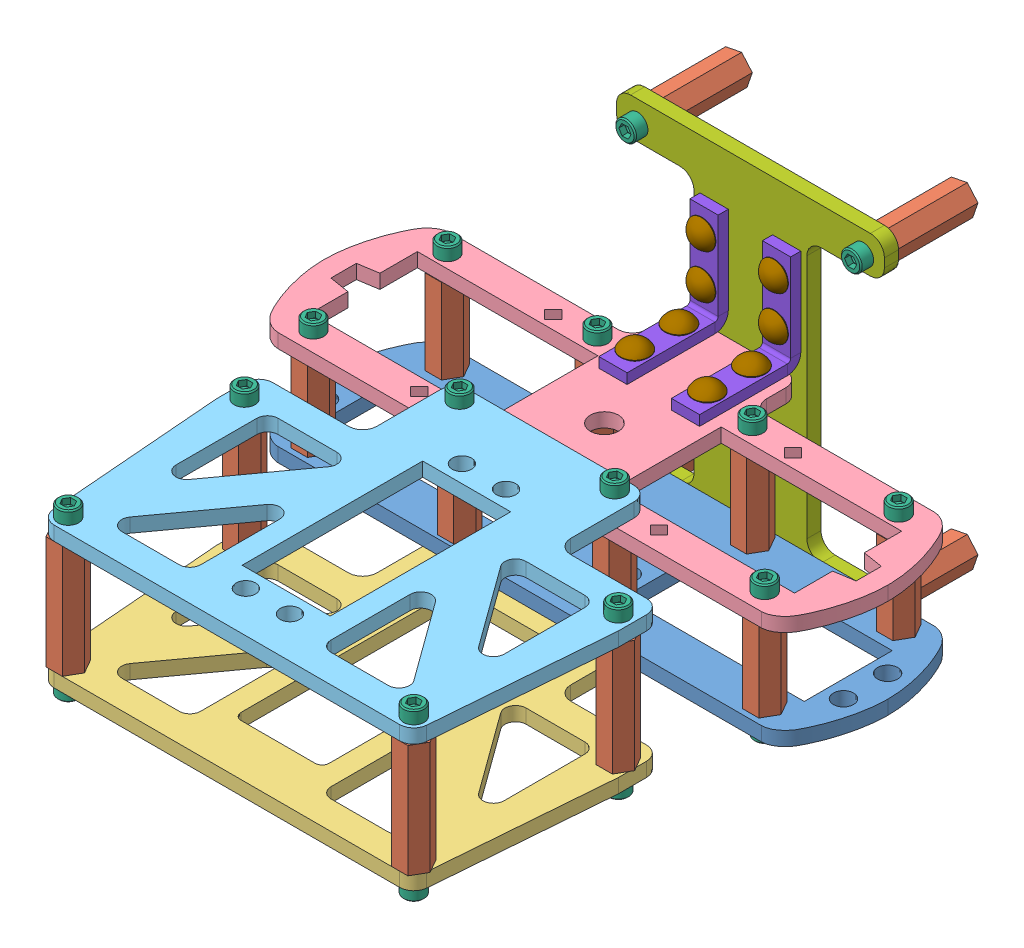
SolidWorks assembly BT-03, configuration Default. Lengths in mm.
Overall size (126.92 78.31 140.07).
59 component instances, 9 part files, 133 mates.
Components (placement in the parent):
- BT-03-001-1: BT-03-001 [Default] x (1 0 0) z (0 1 0) size (126.92 38.86 3.17)
- STANDOFF-250-HEX-FF-9: STANDOFF-250-HEX-FF [NHS-03] at (12.4427 -3.175 39.3112) x (0 -1 0) z (1 0 0) size (25.4 6.35 7.33)
- STANDOFF-250-HEX-FF-10: STANDOFF-250-HEX-FF [NHS-03] at (15.6177 -3.175 82.1737) x (0 -1 0) z (1 0 0) size (25.4 6.35 7.33)
- STANDOFF-250-HEX-FF-11: STANDOFF-250-HEX-FF [NHS-03] at (96.5802 -3.175 39.3112) x (0 -1 0) z (1 0 0) size (25.4 6.35 7.33)
- STANDOFF-250-HEX-FF-12: STANDOFF-250-HEX-FF [NHS-03] at (93.4052 -3.175 82.1737) x (0 -1 0) z (1 0 0) size (25.4 6.35 7.33)
- STANDOFF-250-HEX-FF-1: STANDOFF-250-HEX-FF [NHS-02] at (3.7114 0 -15.0855) x (0 -1 0) z (1 0 0) size (19.05 6.35 7.33)
- STANDOFF-250-HEX-FF-2: STANDOFF-250-HEX-FF [NHS-02] at (37.0489 0 -15.4987) x (0 -1 0) z (1 0 0) size (19.05 6.35 7.33)
- STANDOFF-250-HEX-FF-3: STANDOFF-250-HEX-FF [NHS-02] at (3.7114 0 15.0855) x (0 -1 0) z (1 0 0) size (19.05 6.35 7.33)
- STANDOFF-250-HEX-FF-4: STANDOFF-250-HEX-FF [NHS-02] at (37.0489 0 15.4987) x (0 -1 0) z (1 0 0) size (19.05 6.35 7.33)
- STANDOFF-250-HEX-FF-5: STANDOFF-250-HEX-FF [NHS-02] at (71.9739 0 -15.4987) x (0 -1 0) z (1 0 0) size (19.05 6.35 7.33)
- STANDOFF-250-HEX-FF-6: STANDOFF-250-HEX-FF [NHS-02] at (105.3114 0 -15.0855) x (0 -1 0) z (1 0 0) size (19.05 6.35 7.33)
- STANDOFF-250-HEX-FF-7: STANDOFF-250-HEX-FF [NHS-02] at (71.9739 0 15.4987) x (0 -1 0) z (1 0 0) size (19.05 6.35 7.33)
- STANDOFF-250-HEX-FF-8: STANDOFF-250-HEX-FF [NHS-02] at (105.3114 0 15.0855) x (0 -1 0) z (1 0 0) size (19.05 6.35 7.33)
- BT-03-004-1: BT-03-004 [Default] at (54.5114 -3.175 12.3237) x (1 0 0) z (0 -1 0) size (90.49 73.03 3.17)
- BT-03-002-1: BT-03-002 [Default] at (0 19.05 0) x (1 0 0) z (0 -1 0) size (126.92 49.62 3.17)
- BT-03-003-1: BT-03-003 [Default] at (54.5114 25.4 12.3237) x (1 0 0) z (0 -1 0) size (90.49 73.03 3.17)
- 4-40 x 0.250 SHCS (SHS-01)-1: 4-40 x 0.250 SHCS (SHS-01) [Default] at (3.7114 -6.0198 -15.0855) x (0 1 0) z (0 0 1) size (9.19 4.65 4.65)
- 4-40 x 0.250 SHCS (SHS-01)-2: 4-40 x 0.250 SHCS (SHS-01) [Default] at (37.0489 -6.0198 -15.4987) x (0 1 0) z (0 0 1) size (9.19 4.65 4.65)
- 4-40 x 0.250 SHCS (SHS-01)-3: 4-40 x 0.250 SHCS (SHS-01) [Default] at (3.7114 -6.0198 15.0855) x (0 1 0) z (0 0 1) size (9.19 4.65 4.65)
- 4-40 x 0.250 SHCS (SHS-01)-4: 4-40 x 0.250 SHCS (SHS-01) [Default] at (12.4427 -9.1948 39.3112) x (0 1 0) z (0 0 1) size (9.19 4.65 4.65)
- 4-40 x 0.250 SHCS (SHS-01)-5: 4-40 x 0.250 SHCS (SHS-01) [Default] at (37.0489 -9.1948 15.4987) x (0 1 0) z (0 0 1) size (9.19 4.65 4.65)
- 4-40 x 0.250 SHCS (SHS-01)-6: 4-40 x 0.250 SHCS (SHS-01) [Default] at (71.9739 -6.0198 -15.4987) x (0 1 0) z (0 0 1) size (9.19 4.65 4.65)
- 4-40 x 0.250 SHCS (SHS-01)-7: 4-40 x 0.250 SHCS (SHS-01) [Default] at (15.6177 -9.1948 82.1737) x (0 1 0) z (0 0 1) size (9.19 4.65 4.65)
- 4-40 x 0.250 SHCS (SHS-01)-8: 4-40 x 0.250 SHCS (SHS-01) [Default] at (71.9739 -9.1948 15.4987) x (0 1 0) z (0 0 1) size (9.19 4.65 4.65)
- 4-40 x 0.250 SHCS (SHS-01)-9: 4-40 x 0.250 SHCS (SHS-01) [Default] at (105.3114 -6.0198 -15.0855) x (0 1 0) z (0 0 1) size (9.19 4.65 4.65)
- 4-40 x 0.250 SHCS (SHS-01)-10: 4-40 x 0.250 SHCS (SHS-01) [Default] at (105.3114 -6.0198 15.0855) x (0 1 0) z (0 0 1) size (9.19 4.65 4.65)
- 4-40 x 0.250 SHCS (SHS-01)-11: 4-40 x 0.250 SHCS (SHS-01) [Default] at (96.5802 -9.1948 39.3112) x (0 1 0) z (0 0 1) size (9.19 4.65 4.65)
- 4-40 x 0.250 SHCS (SHS-01)-12: 4-40 x 0.250 SHCS (SHS-01) [Default] at (93.4052 -9.1948 82.1737) x (0 1 0) z (0 0 1) size (9.19 4.65 4.65)
- 4-40 x 0.250 SHCS (SHS-01)-13: 4-40 x 0.250 SHCS (SHS-01) [Default] at (15.6177 28.2448 82.1737) x (0 -1 0) z (0 0 1) size (9.19 4.65 4.65)
- 4-40 x 0.250 SHCS (SHS-01)-14: 4-40 x 0.250 SHCS (SHS-01) [Default] at (12.4427 28.2448 39.3112) x (0 -1 0) z (0 0 1) size (9.19 4.65 4.65)
- 4-40 x 0.250 SHCS (SHS-01)-15: 4-40 x 0.250 SHCS (SHS-01) [Default] at (3.7114 25.0698 15.0855) x (0 -1 0) z (0 0 1) size (9.19 4.65 4.65)
- 4-40 x 0.250 SHCS (SHS-01)-16: 4-40 x 0.250 SHCS (SHS-01) [Default] at (3.7114 25.0698 -15.0855) x (0 -1 0) z (0 0 1) size (9.19 4.65 4.65)
- 4-40 x 0.250 SHCS (SHS-01)-17: 4-40 x 0.250 SHCS (SHS-01) [Default] at (37.0489 25.0698 -15.4987) x (0 -1 0) z (0 0 1) size (9.19 4.65 4.65)
- 4-40 x 0.250 SHCS (SHS-01)-18: 4-40 x 0.250 SHCS (SHS-01) [Default] at (37.0489 28.2448 15.4987) x (0 -1 0) z (0 0 1) size (9.19 4.65 4.65)
- 4-40 x 0.250 SHCS (SHS-01)-19: 4-40 x 0.250 SHCS (SHS-01) [Default] at (71.9739 25.0698 -15.4987) x (0 -1 0) z (0 0 1) size (9.19 4.65 4.65)
- 4-40 x 0.250 SHCS (SHS-01)-20: 4-40 x 0.250 SHCS (SHS-01) [Default] at (71.9739 28.2448 15.4987) x (0 -1 0) z (0 0 1) size (9.19 4.65 4.65)
- 4-40 x 0.250 SHCS (SHS-01)-21: 4-40 x 0.250 SHCS (SHS-01) [Default] at (96.5802 28.2448 39.3112) x (0 -1 0) z (0 0 1) size (9.19 4.65 4.65)
- 4-40 x 0.250 SHCS (SHS-01)-22: 4-40 x 0.250 SHCS (SHS-01) [Default] at (105.3114 25.0698 15.0855) x (0 -1 0) z (0 0 1) size (9.19 4.65 4.65)
- 4-40 x 0.250 SHCS (SHS-01)-23: 4-40 x 0.250 SHCS (SHS-01) [Default] at (105.3114 25.0698 -15.0855) x (0 -1 0) z (0 0 1) size (9.19 4.65 4.65)
- 4-40 x 0.250 SHCS (SHS-01)-24: 4-40 x 0.250 SHCS (SHS-01) [Default] at (93.4052 28.2448 82.1737) x (0 -1 0) z (0 0 1) size (9.19 4.65 4.65)
- BT-03-005-2: BT-03-005 [Default] at (54.5127 56.2839 -35.6692) x (0 -1 0) z (0 0 1) size (78.18 60.32 3.17)
- STANDOFF-250-HEX-FF-13: STANDOFF-250-HEX-FF [NHS-02] at (29.1127 51.4071 -35.6692) x (0 0 1) z (0.656253 -0.754541 0) size (19.05 6.35 7.33)
- 4-40 x 0.250 SHCS (SHS-01)-25: 4-40 x 0.250 SHCS (SHS-01) [Default] at (29.1127 51.4071 -29.6494) x (0 0 -1) z (0.847919 0.530126 0) size (9.19 4.65 4.65)
- STANDOFF-250-HEX-FF-14: STANDOFF-250-HEX-FF [NHS-02] at (79.9127 51.4071 -35.6692) x (0 0 1) z (0.656253 -0.754541 0) size (19.05 6.35 7.33)
- STANDOFF-250-HEX-FF-15: STANDOFF-250-HEX-FF [NHS-02] at (79.9127 -17.1729 -35.6692) x (0 0 1) z (0.656253 -0.754541 0) size (19.05 6.35 7.33)
- STANDOFF-250-HEX-FF-16: STANDOFF-250-HEX-FF [NHS-02] at (29.1127 -17.1729 -35.6692) x (0 0 1) z (0.656253 -0.754541 0) size (19.05 6.35 7.33)
- 4-40 x 0.250 SHCS (SHS-01)-26: 4-40 x 0.250 SHCS (SHS-01) [Default] at (79.9127 51.4071 -29.6494) x (0 0 -1) z (0.847919 0.530126 0) size (9.19 4.65 4.65)
- 4-40 x 0.250 SHCS (SHS-01)-27: 4-40 x 0.250 SHCS (SHS-01) [Default] at (79.9127 -17.1729 -29.6494) x (0 0 -1) z (0.847919 0.530126 0) size (9.19 4.65 4.65)
- 4-40 x 0.250 SHCS (SHS-01)-28: 4-40 x 0.250 SHCS (SHS-01) [Default] at (29.1127 -17.1729 -29.6494) x (0 0 -1) z (0.847919 0.530126 0) size (9.19 4.65 4.65)
- ASB-02-1: ASB-02 [Default] at (46.3516 22.225 -32.4942) x (0 0 1) z (-1 0 0) size (22.78 22.78 6.35)
- ASB-02-2: ASB-02 [Default] at (62.6711 22.225 -32.4942) x (0 0 1) z (-1 0 0) size (22.78 22.78 6.35)
- NSRF-01-1: NSRF-01 [Default] at (46.3516 27.1043 -14.6126) x (0 -1 0) z (0 0 1) size (9.65 6.35 6.35)
- NSRF-01-2: NSRF-01 [Default] at (46.3516 27.1043 -24.5516) x (0 -1 0) z (0 0 1) size (9.65 6.35 6.35)
- NSRF-01-3: NSRF-01 [Default] at (46.3516 40.1066 -27.6149) x (0 0 -1) z (0.995672 0.092934 0) size (9.65 6.35 6.35)
- NSRF-01-4: NSRF-01 [Default] at (62.6711 27.1043 -14.6126) x (0 -1 0) z (0 0 1) size (9.65 6.35 6.35)
- NSRF-01-5: NSRF-01 [Default] at (62.6711 27.1043 -24.5516) x (0 -1 0) z (0 0 1) size (9.65 6.35 6.35)
- NSRF-01-6: NSRF-01 [Default] at (62.6711 40.1066 -27.6149) x (0 0 -1) z (1 0 0) size (9.65 6.35 6.35)
- NSRF-01-7: NSRF-01 [Default] at (46.3516 30.1676 -27.6149) x (0 0 -1) z (1 0 0) size (9.65 6.35 6.35)
- NSRF-01-8: NSRF-01 [Default] at (62.6711 30.1676 -27.6149) x (0 0 -1) z (1 0 0) size (9.65 6.35 6.35)
Mates (geometry in assembly coordinates):
- Coincident1: coincident aligned: plane of BT-03-001-1 through (0 0 0) normal (1 0 0); plane of assembly
- Coincident2: coincident anti-aligned: plane of BT-03-001-1 through (0 0 0) normal (0 0 -1); plane of assembly
- Coincident3: coincident aligned: plane of BT-03-001-1 through (0 0 0) normal (0 1 0); plane of assembly
- Coincident4: coincident anti-aligned: plane of BT-03-001-1 through (-6.866 0 -11.2321) normal (0 1 0); plane of STANDOFF-250-HEX-FF-1
- Concentric1: concentric anti-aligned: circle of BT-03-001-1 centre (3.7114 0 -15.0855) axis (0 1 0); cylinder of STANDOFF-250-HEX-FF-1
- Parallel1: parallel aligned: plane of BT-03-001-1 through (0 -3.175 -9.906) normal (0 0 1); plane of STANDOFF-250-HEX-FF-1
- Concentric2: concentric anti-aligned: circle of BT-03-001-1 centre (37.0489 0 -15.4987) axis (0 1 0); cylinder of STANDOFF-250-HEX-FF-2
- Coincident6: coincident anti-aligned: plane of BT-03-001-1 through (-6.866 0 -11.2321) normal (0 1 0); plane of STANDOFF-250-HEX-FF-2
- Parallel2: parallel aligned: plane of BT-03-001-1 through (0 -3.175 -9.906) normal (0 0 1); plane of STANDOFF-250-HEX-FF-2
- Concentric3: concentric aligned: circle of BT-03-001-1 centre (3.7114 0 15.0855) axis (0 -1 0); cylinder of STANDOFF-250-HEX-FF-3
- Coincident7: coincident anti-aligned: plane of BT-03-001-1 through (-6.866 0 -11.2321) normal (0 1 0); plane of STANDOFF-250-HEX-FF-3
- Parallel3: parallel aligned: plane of BT-03-001-1 through (108.8801 -3.175 19.431) normal (0 0 1); plane of STANDOFF-250-HEX-FF-3
- Concentric4: concentric aligned: circle of BT-03-001-1 centre (37.0489 0 15.4987) axis (0 -1 0); cylinder of STANDOFF-250-HEX-FF-4
- Coincident9: coincident anti-aligned: plane of BT-03-001-1 through (-6.866 0 -11.2321) normal (0 1 0); plane of STANDOFF-250-HEX-FF-4
- Parallel4: parallel aligned: plane of BT-03-001-1 through (108.8801 -3.175 19.431) normal (0 0 1); plane of STANDOFF-250-HEX-FF-4
- Coincident10: coincident anti-aligned: plane of BT-03-001-1 through (-6.866 0 -11.2321) normal (0 1 0); plane of STANDOFF-250-HEX-FF-5
- Concentric5: concentric aligned: circle of BT-03-001-1 centre (71.9739 0 -15.4987) axis (0 -1 0); cylinder of STANDOFF-250-HEX-FF-5
- Parallel5: parallel aligned: plane of BT-03-001-1 through (68.3826 -3.175 -9.906) normal (0 0 1); plane of STANDOFF-250-HEX-FF-5
- Concentric6: concentric aligned: circle of BT-03-001-1 centre (105.3114 0 -15.0855) axis (0 -1 0); cylinder of STANDOFF-250-HEX-FF-6
- Coincident11: coincident anti-aligned: plane of BT-03-001-1 through (-6.866 0 -11.2321) normal (0 1 0); plane of STANDOFF-250-HEX-FF-6
- Parallel6: parallel aligned: plane of BT-03-001-1 through (68.3826 -3.175 -9.906) normal (0 0 1); plane of STANDOFF-250-HEX-FF-6
- Concentric7: concentric anti-aligned: circle of BT-03-001-1 centre (71.9739 0 15.4987) axis (0 1 0); cylinder of STANDOFF-250-HEX-FF-7
- Concentric8: concentric anti-aligned: circle of BT-03-001-1 centre (105.3114 0 15.0855) axis (0 1 0); cylinder of STANDOFF-250-HEX-FF-8
- Coincident12: coincident anti-aligned: plane of BT-03-001-1 through (-6.866 0 -11.2321) normal (0 1 0); plane of STANDOFF-250-HEX-FF-8
- Parallel7: parallel aligned: plane of BT-03-001-1 through (108.8801 -3.175 19.431) normal (0 0 1); plane of STANDOFF-250-HEX-FF-8
- Coincident13: coincident anti-aligned: plane of BT-03-001-1 through (-6.866 0 -11.2321) normal (0 1 0); plane of STANDOFF-250-HEX-FF-7
- Parallel8: parallel aligned: plane of BT-03-001-1 through (108.8801 -3.175 19.431) normal (0 0 1); plane of STANDOFF-250-HEX-FF-7
- Coincident14: coincident anti-aligned: plane of BT-03-001-1 through (-6.866 -3.175 -11.2321) normal (0 -1 0); plane of BT-03-004-1 through (96.5802 -3.175 36.1362) normal (0 1 0)
- Concentric9: concentric anti-aligned: circle of BT-03-001-1 centre (37.0489 0 15.4987) axis (0 -1 0); circle of BT-03-004-1 centre (37.0489 -3.175 15.4987) axis (0 1 0)
- Concentric11: concentric anti-aligned: circle of BT-03-001-1 centre (71.9739 0 15.4987) axis (0 1 0); circle of BT-03-004-1 centre (71.9739 -3.175 15.4987) axis (0 -1 0)
- Coincident18: coincident anti-aligned: plane of STANDOFF-250-HEX-FF-3; plane of BT-03-002-1 through (44.1927 19.05 -27.013) normal (0 -1 0)
- Concentric12: concentric aligned: circle of BT-03-001-1 centre (3.7114 0 15.0855) axis (0 -1 0); circle of BT-03-002-1 centre (3.7114 19.05 15.0855) axis (0 -1 0)
- Coincident20: coincident aligned: plane of BT-03-001-1 through (108.8801 -3.175 19.431) normal (0 0 1); plane of BT-03-002-1 through (108.8801 22.225 19.431) normal (0 0 1)
- Concentric13: concentric anti-aligned: circle of BT-03-004-1 centre (12.4427 -3.175 39.3112) axis (0 1 0); cylinder of STANDOFF-250-HEX-FF-9
- Coincident21: coincident anti-aligned: plane of BT-03-004-1 through (96.5802 -3.175 36.1362) normal (0 1 0); plane of STANDOFF-250-HEX-FF-9
- Concentric14: concentric anti-aligned: circle of BT-03-004-1 centre (15.6177 -3.175 82.1737) axis (0 1 0); cylinder of STANDOFF-250-HEX-FF-10
- Coincident22: coincident anti-aligned: plane of BT-03-004-1 through (96.5802 -3.175 36.1362) normal (0 1 0); plane of STANDOFF-250-HEX-FF-10
- Concentric15: concentric aligned: circle of BT-03-004-1 centre (96.5802 -3.175 39.3112) axis (0 -1 0); cylinder of STANDOFF-250-HEX-FF-11
- Coincident24: coincident anti-aligned: plane of BT-03-004-1 through (96.5802 -3.175 36.1362) normal (0 1 0); plane of STANDOFF-250-HEX-FF-11
- Concentric16: concentric aligned: circle of BT-03-004-1 centre (93.4052 -3.175 82.1737) axis (0 -1 0); cylinder of STANDOFF-250-HEX-FF-12
- Coincident25: coincident anti-aligned: plane of BT-03-004-1 through (96.5802 -3.175 36.1362) normal (0 1 0); plane of STANDOFF-250-HEX-FF-12
- Coincident26: coincident anti-aligned: plane of BT-03-002-1 through (44.1927 22.225 -27.013) normal (0 1 0); plane of BT-03-003-1 through (96.5802 22.225 36.1362) normal (0 -1 0)
- Concentric17: concentric anti-aligned: circle of BT-03-002-1 centre (37.0489 19.05 15.4987) axis (0 -1 0); circle of BT-03-003-1 centre (37.0489 25.4 15.4987) axis (0 1 0)
- Concentric18: concentric anti-aligned: circle of BT-03-002-1 centre (71.9739 19.05 15.4987) axis (0 1 0); circle of BT-03-003-1 centre (71.9739 25.4 15.4987) axis (0 -1 0)
- Concentric191: concentric aligned: cylinder of STANDOFF-250-HEX-FF-10; cylinder of 4-40 x 0.250 SHCS (SHS-01)-13
- Distance10: distance = 3.175 mm anti-aligned: plane of STANDOFF-250-HEX-FF-10; plane of 4-40 x 0.250 SHCS (SHS-01)-13
- Concentric201: concentric aligned: cylinder of STANDOFF-250-HEX-FF-9; cylinder of 4-40 x 0.250 SHCS (SHS-01)-14
- Distance9: distance = 3.175 mm anti-aligned: plane of STANDOFF-250-HEX-FF-9; plane of 4-40 x 0.250 SHCS (SHS-01)-14
- Concentric211: concentric aligned: cylinder of STANDOFF-250-HEX-FF-3; cylinder of 4-40 x 0.250 SHCS (SHS-01)-15
- Distance8: distance = 3.175 mm anti-aligned: plane of STANDOFF-250-HEX-FF-3; plane of 4-40 x 0.250 SHCS (SHS-01)-15
- Concentric221: concentric aligned: cylinder of STANDOFF-250-HEX-FF-1; cylinder of 4-40 x 0.250 SHCS (SHS-01)-16
- Distance7: distance = 3.175 mm anti-aligned: plane of STANDOFF-250-HEX-FF-1; plane of 4-40 x 0.250 SHCS (SHS-01)-16
- Concentric231: concentric aligned: cylinder of STANDOFF-250-HEX-FF-2; cylinder of 4-40 x 0.250 SHCS (SHS-01)-17
- Distance5: distance = 3.175 mm anti-aligned: plane of STANDOFF-250-HEX-FF-2; plane of 4-40 x 0.250 SHCS (SHS-01)-17
- Concentric241: concentric aligned: cylinder of STANDOFF-250-HEX-FF-4; cylinder of 4-40 x 0.250 SHCS (SHS-01)-18
- Distance6: distance = 6.35 mm anti-aligned: plane of STANDOFF-250-HEX-FF-4; plane of 4-40 x 0.250 SHCS (SHS-01)-18
- Concentric251: concentric aligned: cylinder of STANDOFF-250-HEX-FF-5; cylinder of 4-40 x 0.250 SHCS (SHS-01)-19
- Distance4: distance = 3.175 mm anti-aligned: plane of STANDOFF-250-HEX-FF-5; plane of 4-40 x 0.250 SHCS (SHS-01)-19
- Concentric261: concentric aligned: cylinder of STANDOFF-250-HEX-FF-7; cylinder of 4-40 x 0.250 SHCS (SHS-01)-20
- Distance1: distance = 6.35 mm anti-aligned: plane of STANDOFF-250-HEX-FF-7; plane of 4-40 x 0.250 SHCS (SHS-01)-20
- Concentric271: concentric aligned: cylinder of STANDOFF-250-HEX-FF-11; cylinder of 4-40 x 0.250 SHCS (SHS-01)-21
- Distance11: distance = 3.175 mm anti-aligned: plane of STANDOFF-250-HEX-FF-11; plane of 4-40 x 0.250 SHCS (SHS-01)-21
- Concentric281: concentric aligned: cylinder of STANDOFF-250-HEX-FF-8; cylinder of 4-40 x 0.250 SHCS (SHS-01)-22
- Distance2: distance = 3.175 mm anti-aligned: plane of STANDOFF-250-HEX-FF-8; plane of 4-40 x 0.250 SHCS (SHS-01)-22
- Concentric291: concentric aligned: cylinder of STANDOFF-250-HEX-FF-6; cylinder of 4-40 x 0.250 SHCS (SHS-01)-23
- Distance3: distance = 3.175 mm anti-aligned: plane of STANDOFF-250-HEX-FF-6; plane of 4-40 x 0.250 SHCS (SHS-01)-23
- Concentric301: concentric aligned: cylinder of STANDOFF-250-HEX-FF-12; cylinder of 4-40 x 0.250 SHCS (SHS-01)-24
- Distance12: distance = 3.175 mm anti-aligned: plane of STANDOFF-250-HEX-FF-12; plane of 4-40 x 0.250 SHCS (SHS-01)-24
- Concentric311: concentric aligned: cylinder of STANDOFF-250-HEX-FF-1; cylinder of 4-40 x 0.250 SHCS (SHS-01)-1
- Distance13: distance = 3.175 mm anti-aligned: plane of STANDOFF-250-HEX-FF-1; plane of 4-40 x 0.250 SHCS (SHS-01)-1
- Concentric321: concentric aligned: cylinder of STANDOFF-250-HEX-FF-2; cylinder of 4-40 x 0.250 SHCS (SHS-01)-2
- Distance14: distance = 3.175 mm anti-aligned: plane of STANDOFF-250-HEX-FF-2; plane of 4-40 x 0.250 SHCS (SHS-01)-2
- Concentric331: concentric aligned: cylinder of STANDOFF-250-HEX-FF-3; cylinder of 4-40 x 0.250 SHCS (SHS-01)-3
- Distance20: distance = 3.175 mm anti-aligned: plane of STANDOFF-250-HEX-FF-3; plane of 4-40 x 0.250 SHCS (SHS-01)-3
- Concentric341: concentric aligned: cylinder of STANDOFF-250-HEX-FF-9; cylinder of 4-40 x 0.250 SHCS (SHS-01)-4
- Distance22: distance = 3.175 mm anti-aligned: plane of STANDOFF-250-HEX-FF-9; plane of 4-40 x 0.250 SHCS (SHS-01)-4
- Concentric351: concentric aligned: cylinder of STANDOFF-250-HEX-FF-4; cylinder of 4-40 x 0.250 SHCS (SHS-01)-5
- Distance19: distance = 6.35 mm anti-aligned: plane of STANDOFF-250-HEX-FF-4; plane of 4-40 x 0.250 SHCS (SHS-01)-5
- Concentric361: concentric aligned: cylinder of STANDOFF-250-HEX-FF-5; cylinder of 4-40 x 0.250 SHCS (SHS-01)-6
- Distance15: distance = 3.175 mm anti-aligned: plane of STANDOFF-250-HEX-FF-5; plane of 4-40 x 0.250 SHCS (SHS-01)-6
- Concentric371: concentric aligned: cylinder of STANDOFF-250-HEX-FF-10; cylinder of 4-40 x 0.250 SHCS (SHS-01)-7
- Distance23: distance = 3.175 mm anti-aligned: plane of STANDOFF-250-HEX-FF-10; plane of 4-40 x 0.250 SHCS (SHS-01)-7
- Concentric381: concentric aligned: cylinder of STANDOFF-250-HEX-FF-7; cylinder of 4-40 x 0.250 SHCS (SHS-01)-8
- Distance18: distance = 6.35 mm anti-aligned: plane of STANDOFF-250-HEX-FF-7; plane of 4-40 x 0.250 SHCS (SHS-01)-8
- Concentric391: concentric aligned: cylinder of STANDOFF-250-HEX-FF-6; cylinder of 4-40 x 0.250 SHCS (SHS-01)-9
- Distance16: distance = 3.175 mm anti-aligned: plane of STANDOFF-250-HEX-FF-6; plane of 4-40 x 0.250 SHCS (SHS-01)-9
- Concentric401: concentric aligned: cylinder of STANDOFF-250-HEX-FF-8; cylinder of 4-40 x 0.250 SHCS (SHS-01)-10
- Distance17: distance = 3.175 mm anti-aligned: plane of STANDOFF-250-HEX-FF-8; plane of 4-40 x 0.250 SHCS (SHS-01)-10
- Concentric411: concentric aligned: cylinder of STANDOFF-250-HEX-FF-11; cylinder of 4-40 x 0.250 SHCS (SHS-01)-11
- Distance21: distance = 3.175 mm anti-aligned: plane of STANDOFF-250-HEX-FF-11; plane of 4-40 x 0.250 SHCS (SHS-01)-11
- Concentric421: concentric aligned: cylinder of STANDOFF-250-HEX-FF-12; cylinder of 4-40 x 0.250 SHCS (SHS-01)-12
- Distance24: distance = 3.175 mm anti-aligned: plane of STANDOFF-250-HEX-FF-12; plane of 4-40 x 0.250 SHCS (SHS-01)-12
- Concentric43: concentric aligned: circle of BT-03-005-2 centre (29.1127 51.4071 -35.6692) axis (0 0 1); cylinder of STANDOFF-250-HEX-FF-13
- Coincident53: coincident anti-aligned: plane of BT-03-005-2 through (27.5252 53.1089 -35.6692) normal (0 0 -1); plane of STANDOFF-250-HEX-FF-13
- Coincident54: coincident anti-aligned: plane of BT-03-005-2 through (27.5252 53.1089 -32.4942) normal (0 0 1); plane of 4-40 x 0.250 SHCS (SHS-01)-25
- Concentric44: concentric aligned: cylinder of STANDOFF-250-HEX-FF-13; cylinder of 4-40 x 0.250 SHCS (SHS-01)-25
- Concentric45: concentric anti-aligned: circle of BT-03-005-2 centre (79.9127 51.4071 -35.6692) axis (0 0 -1); cylinder of STANDOFF-250-HEX-FF-14
- Coincident55: coincident anti-aligned: plane of BT-03-005-2 through (27.5252 53.1089 -35.6692) normal (0 0 -1); plane of STANDOFF-250-HEX-FF-14
- Coincident56: coincident anti-aligned: plane of BT-03-005-2 through (27.5252 53.1089 -35.6692) normal (0 0 -1); plane of STANDOFF-250-HEX-FF-15
- Coincident57: coincident anti-aligned: plane of BT-03-005-2 through (27.5252 53.1089 -35.6692) normal (0 0 -1); plane of STANDOFF-250-HEX-FF-16
- Concentric46: concentric anti-aligned: circle of BT-03-005-2 centre (79.9127 -17.1729 -35.6692) axis (0 0 -1); cylinder of STANDOFF-250-HEX-FF-15
- Concentric47: concentric aligned: circle of BT-03-005-2 centre (29.1127 -17.1729 -35.6692) axis (0 0 1); cylinder of STANDOFF-250-HEX-FF-16
- Coincident58: coincident anti-aligned: plane of BT-03-005-2 through (27.5252 53.1089 -32.4942) normal (0 0 1); plane of 4-40 x 0.250 SHCS (SHS-01)-26
- Concentric48: concentric aligned: cylinder of STANDOFF-250-HEX-FF-14; cylinder of 4-40 x 0.250 SHCS (SHS-01)-26
- Coincident59: coincident anti-aligned: plane of BT-03-005-2 through (27.5252 53.1089 -32.4942) normal (0 0 1); plane of 4-40 x 0.250 SHCS (SHS-01)-28
- Concentric49: concentric aligned: cylinder of STANDOFF-250-HEX-FF-16; cylinder of 4-40 x 0.250 SHCS (SHS-01)-28
- Coincident60: coincident anti-aligned: plane of BT-03-005-2 through (27.5252 53.1089 -32.4942) normal (0 0 1); plane of 4-40 x 0.250 SHCS (SHS-01)-27
- Concentric50: concentric aligned: cylinder of STANDOFF-250-HEX-FF-15; cylinder of 4-40 x 0.250 SHCS (SHS-01)-27
- Coincident61: coincident anti-aligned: plane of BT-03-002-1 through (44.1927 22.225 -27.013) normal (0 1 0); plane of ASB-02-1 through (43.1766 22.225 -32.4942) normal (0 -1 0)
- Coincident62: coincident anti-aligned: plane of BT-03-002-1 through (44.1927 22.225 -27.013) normal (0 1 0); plane of ASB-02-2 through (59.4962 22.225 -32.4942) normal (0 -1 0)
- Coincident63: coincident anti-aligned: plane of BT-03-005-2 through (27.5252 53.1089 -32.4942) normal (0 0 1); plane of ASB-02-1 through (43.1766 22.225 -32.4942) normal (0 0 -1)
- Concentric55: concentric aligned: cylinder of BT-03-005-2; cylinder of ASB-02-1
- Parallel9: parallel aligned: plane of BT-03-005-2 through (67.2127 44.7745 -32.4942) normal (1 0 0); plane of ASB-02-2 through (65.8462 45.0088 11.3046) normal (1 0 0)
- Concentric561: concentric aligned: cylinder of ASB-02-1; cylinder of NSRF-01-1
- Coincident641: coincident anti-aligned: plane of ASB-02-1 through (43.1766 24.511 -30.2082) normal (0 1 0); plane of NSRF-01-1 through (47.6295 24.511 -14.6126) normal (0 -1 0)
- Concentric571: concentric aligned: cylinder of ASB-02-1; cylinder of NSRF-01-2
- Coincident651: coincident anti-aligned: plane of ASB-02-1 through (43.1766 24.511 -30.2082) normal (0 1 0); plane of NSRF-01-2 through (47.6295 24.511 -24.5516) normal (0 -1 0)
- Concentric581: concentric anti-aligned: cylinder of ASB-02-1; cylinder of NSRF-01-3
- Coincident661: coincident anti-aligned: plane of ASB-02-1 through (43.1766 45.0088 -30.2082) normal (0 0 1); plane of NSRF-01-3 through (46.2329 41.3789 -30.2082) normal (0 0 -1)
- Concentric591: concentric aligned: cylinder of ASB-02-2; cylinder of NSRF-01-4
- Coincident671: coincident anti-aligned: plane of ASB-02-2 through (59.4962 24.511 -30.2082) normal (0 1 0); plane of NSRF-01-4 through (63.949 24.511 -14.6126) normal (0 -1 0)
- Concentric611: concentric aligned: cylinder of ASB-02-2; cylinder of NSRF-01-5
- Coincident691: coincident anti-aligned: plane of ASB-02-2 through (59.4962 24.511 -30.2082) normal (0 1 0); plane of NSRF-01-5 through (63.949 24.511 -24.5516) normal (0 -1 0)
- Concentric621: concentric anti-aligned: cylinder of ASB-02-2; cylinder of NSRF-01-6
- Coincident701: coincident anti-aligned: plane of ASB-02-2 through (59.4962 45.0088 -30.2082) normal (0 0 1); plane of NSRF-01-6 through (62.6711 41.3844 -30.2082) normal (0 0 -1)
- Concentric631: concentric anti-aligned: cylinder of ASB-02-1; cylinder of NSRF-01-7
- Coincident711: coincident anti-aligned: plane of ASB-02-1 through (43.1766 45.0088 -30.2082) normal (0 0 1); plane of NSRF-01-7 through (46.3516 31.4454 -30.2082) normal (0 0 -1)
- Concentric641: concentric anti-aligned: cylinder of ASB-02-2; cylinder of NSRF-01-8
- Coincident721: coincident anti-aligned: plane of ASB-02-2 through (59.4962 45.0088 -30.2082) normal (0 0 1); plane of NSRF-01-8 through (62.6711 31.4454 -30.2082) normal (0 0 -1)
- Concentric642: concentric anti-aligned: cylinder of BT-03-002-1; cylinder of ASB-02-2
- Parallel10: parallel aligned: plane of BT-03-002-1 through (68.0052 22.225 -27.013) normal (1 0 0); plane of ASB-02-2 through (65.8462 66.0238 -30.2082) normal (1 0 0)
- Concentric643: concentric anti-aligned: cylinder of BT-03-002-1; cylinder of ASB-02-1
- Parallel11: parallel aligned: plane of ASB-02-1 through (49.5266 66.0238 -30.2082) normal (1 0 0); plane of ASB-02-2 through (65.8462 66.0238 -30.2082) normal (1 0 0)
